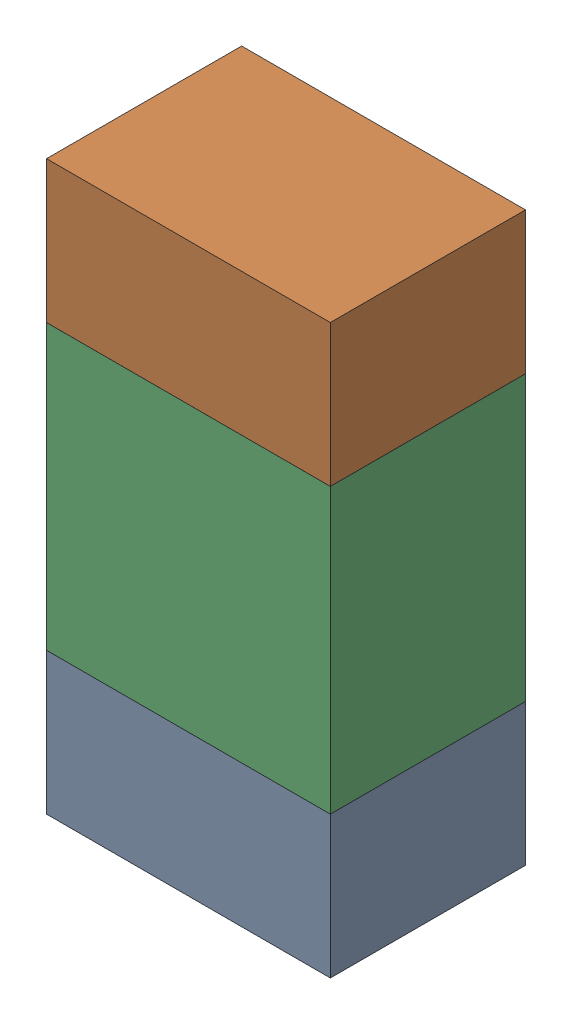
SolidWorks assembly R18, configuration ﾃﾞﾌｫﾙﾄ. Lengths in mm.
Overall size (0.8 1.6 0.55).
6 component instances, 2 part files, 0 mates.
Components (placement in the parent):
- 689261784-1: 689261784 [ﾃﾞﾌｫﾙﾄ] at (39.6874 29.8801 0) size (0.8 0.4 0.55)
  - Extruded_34-1: Extruded_34 [ﾃﾞﾌｫﾙﾄ] at origin size (0.8 0.4 0.55)
- 689261784-2: 689261784 [ﾃﾞﾌｫﾙﾄ] at (39.6874 31.0801 0) size (0.8 0.4 0.55)
  - Extruded_34-1: Extruded_34 [ﾃﾞﾌｫﾙﾄ] at origin size (0.8 0.4 0.55)
- 689261648-1: 689261648 [ﾃﾞﾌｫﾙﾄ] at (39.6874 30.48 0) size (0.8 0.8 0.55)
  - Extruded_33-1: Extruded_33 [ﾃﾞﾌｫﾙﾄ] at origin size (0.8 0.8 0.55)
